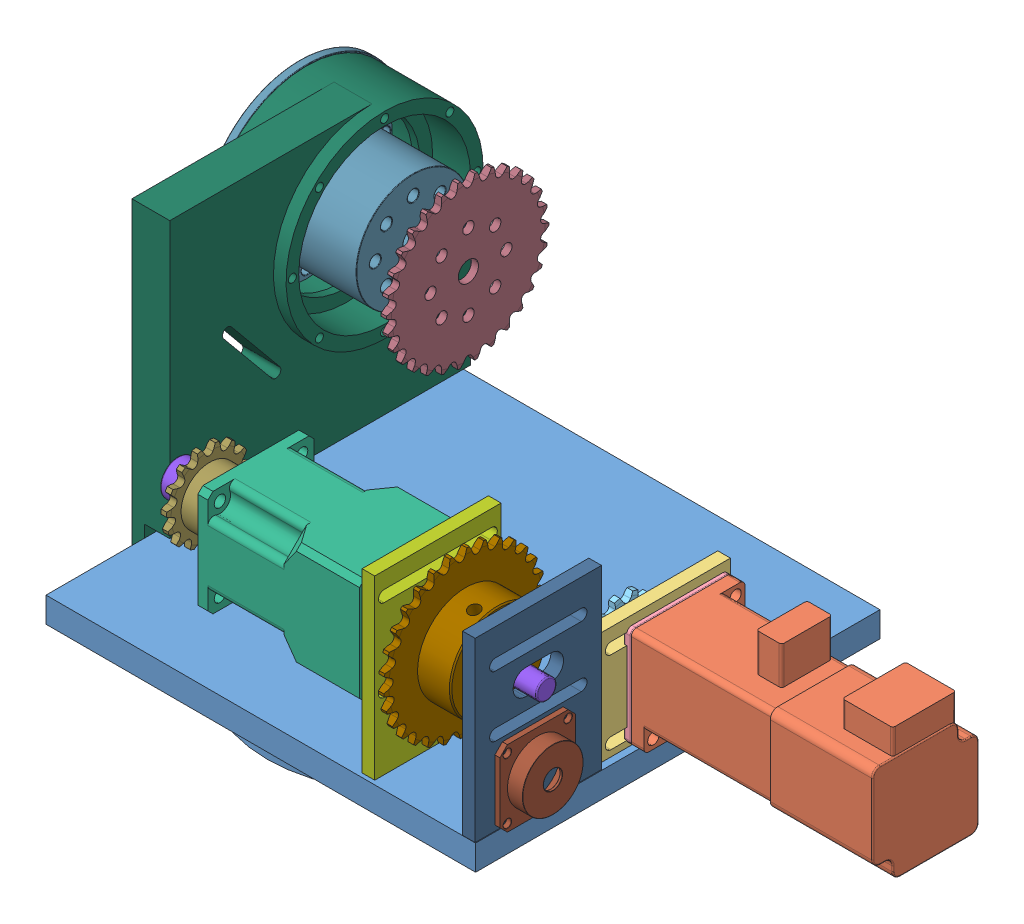
SolidWorks assembly joint 2 assembly, configuration Default. Lengths in mm.
Overall size (284.51 129.16 179.38).
15 component instances, 15 part files, 20 mates.
Components (placement in the parent):
- joint 1 turret cap-1: joint 1 turret cap [Default] at (36.3572 68.2454 195.7007) x (-1 0 0) z (0 0 -1) size (170 15 160)
- mitsu 100W motor-1: mitsu 100W motor [Default] at (125.3653 119.2454 190.6155) x (0 0 -1) z (0 1 0) size (42 121 56)
- servo100w hold-1: servo100w hold [Default] at (118.6019 101.3922 121.9888) x (0 0 1) z (0 -1 0) size (52.01 5 44.5)
- on the servo 200W-1: on the servo 200W [Default] at (117.3653 99.2454 170.6155) x (0 0 -1) z (0 -1 0) size (40 3 40)
- 25B10 fixed-1: 25B10 fixed [25B10] at (95.8653 99.2454 170.6155) x (0 0 1) z (0 -1 0) size (23.35 12.7 22.79)
- gear 100W-1: gear 100W [Default] at (10.8514 123.2454 231.6142) x (0 0 1) z (0 -1 0) size (42 67 42)
- tang dua gear-1: tang dua gear [Default] at (79.8514 109.971 231.1893) x (0 0 1) z (0 -1 0) size (50 5 70)
- long cylinder-1: long cylinder [Default] at (66.8514 123.2454 231.6142) x (0 0.10207 -0.994777) z (0 -0.994777 -0.10207) size (14 146 14)
- SP25B30 fixede-1: SP25B30 fixede [25B30] at (93.0466 123.2454 231.6142) x (0 -0.270532 0.962711) z (0 -0.962711 -0.270532) size (64.23 15.88 63.98)
- tang dua dong co-1: tang dua dong co [Default] at (116.0852 104.971 218.5403) x (0 0 -1) z (0 -1 0) size (50 5 70)
- bearing_stretch-1: bearing_stretch [Default] at (150.3298 119.6559 257.5761) x (0 -1 0) z (0 0 -1) size (30 8 30)
- 15teeths_14mm-1: 15teeths_14mm [25B15] at (-8.2538 123.2454 231.6142) x (0 0.22013 -0.97547) z (0 0.97547 0.22013) size (33.63 12.7 33.47)
- 30teeths_turret-1: 30teeths_turret [25B30] at (-3.6119 153.4022 133.8727) x (0 0 1) z (0 -1 0) size (64.23 2.79 63.98)
- Joint2 turret-1: Joint2 turret [Default] at (-22.6428 153.4022 133.8727) x (0 0 1) z (-1 0 0) size (78 78 45)
- side part joint2-2: side part joint2 [Default] at (-48.6428 153.0673 134.2158) x (0 0 -1) z (0 -1 0) size (119 31 119)
Mates (geometry in assembly coordinates):
- Coincident2: coincident anti-aligned: plane of joint 1 turret cap-1 through (36.3572 78.2454 195.7007) normal (0 1 0); plane of servo100w hold-1 through (123.6019 78.2454 121.9888) normal (0 -1 0)
- Concentric1: concentric aligned: cylinder of mitsu 100W motor-1 through (95.8653 99.2454 170.6155) axis (1 0 0) radius 4; cylinder of servo100w hold-1 through (113.6019 99.2454 170.6155) axis (1 0 0) radius 4
- Concentric2: concentric anti-aligned: cylinder of mitsu 100W motor-1 through (117.8653 99.2454 170.6155) axis (1 0 0) radius 15; cylinder of on the servo 200W-1 through (120.3653 99.2454 170.6155) axis (-1 0 0) radius 15
- Coincident3: coincident anti-aligned: plane of mitsu 100W motor-1 through (120.3653 81.2454 152.6155) normal (-1 0 0); plane of on the servo 200W-1 through (120.3653 81.2454 152.6155) normal (1 0 0)
- Concentric3: concentric anti-aligned: cylinder of servo100w hold-1 through (113.6019 115.5088 154.3521) axis (1 0 0) radius 2.25; cylinder of on the servo 200W-1 through (120.3653 115.5088 154.3521) axis (-1 0 0) radius 2.25
- Concentric4: concentric aligned: cylinder of mitsu 100W motor-1 through (95.8653 99.2454 170.6155) axis (1 0 0) radius 4; cylinder of 25B10 fixed-1 through (95.8653 99.2454 170.6155) axis (1 0 0) radius 4
- Coincident4: coincident aligned: plane of mitsu 100W motor-1 through (95.8653 99.2454 170.6155) normal (-1 0 0); plane of 25B10 fixed-1 through (95.8653 99.2454 170.6155) normal (-1 0 0)
- Coincident5: coincident anti-aligned: plane of joint 1 turret cap-1 through (36.3572 78.2454 195.7007) normal (0 1 0); plane of tang dua gear-1 through (74.8514 78.2454 201.6142) normal (0 -1 0)
- Coincident6: coincident anti-aligned: plane of gear 100W-1 through (74.8514 123.2454 231.6142) normal (1 0 0); plane of tang dua gear-1 through (74.8514 109.971 231.1893) normal (-1 0 0)
- Concentric5: concentric aligned: cylinder of gear 100W-1 through (69.8514 139.5088 247.8777) axis (1 0 0) radius 2.25; cylinder of tang dua gear-1 through (74.8514 139.5088 247.8777) axis (1 0 0) radius 2.25
- Concentric6: concentric anti-aligned: cylinder of gear 100W-1 through (74.8514 123.2454 231.6142) axis (-1 0 0) radius 7; cylinder of long cylinder-1 through (-18.1486 123.2454 231.6142) axis (1 0 0) radius 7
- Distance1: distance = 26 mm aligned: plane of long cylinder-1 through (-18.1486 123.2454 231.6142) normal (-1 0 0); plane of gear 100W-1 through (7.8514 123.2454 231.6142) normal (-1 0 0)
- Concentric7: concentric anti-aligned: cylinder of long cylinder-1 through (127.8514 123.2454 231.6142) axis (-1 0 0) radius 4; cylinder of SP25B30 fixede-1 through (93.0466 123.2454 231.6142) axis (1 0 0) radius 4
- Concentric8: concentric aligned: cylinder of mitsu 100W motor-1 through (131.7292 82.9819 186.879) axis (-1 0 0) radius 2.25; cylinder of on the servo 200W-1 through (120.3653 82.9819 186.879) axis (-1 0 0) radius 2.25
- Coincident9: coincident aligned: plane of tang dua gear-1 through (74.8514 148.2454 201.6142) normal (0 1 0); plane of tang dua dong co-1 through (121.0852 148.2454 253.1154) normal (0 1 0)
- Concentric12: concentric aligned: cylinder of long cylinder-1 through (-18.1486 123.2454 231.6142) axis (1 0 0) radius 7; cylinder of 15teeths_14mm-1 through (-9.5538 123.2454 231.6142) axis (1 0 0) radius 7
- Concentric13: concentric aligned: cylinder of 30teeths_turret-1 through (-10.8179 168.4022 133.8727) axis (1 0 0) radius 2.25; cylinder of Joint2 turret-1 through (-32.6428 168.4022 133.8727) axis (1 0 0) radius 2.25
- Concentric14: concentric aligned: cylinder of 30teeths_turret-1 through (-10.8179 138.4022 133.8727) axis (1 0 0) radius 2.25; cylinder of Joint2 turret-1 through (-32.6428 138.4022 133.8727) axis (1 0 0) radius 2.25
- Coincident11: coincident anti-aligned: plane of joint 1 turret cap-1 through (-48.6428 78.2454 195.7007) normal (-1 0 0); plane of side part joint2-2 through (-48.6428 153.0673 134.2158) normal (1 0 0)
- Coincident12: coincident anti-aligned: plane of Joint2 turret-1 through (-64.6428 153.4022 133.8727) normal (1 0 0); plane of side part joint2-2 through (-64.6428 153.0673 134.2158) normal (-1 0 0)
